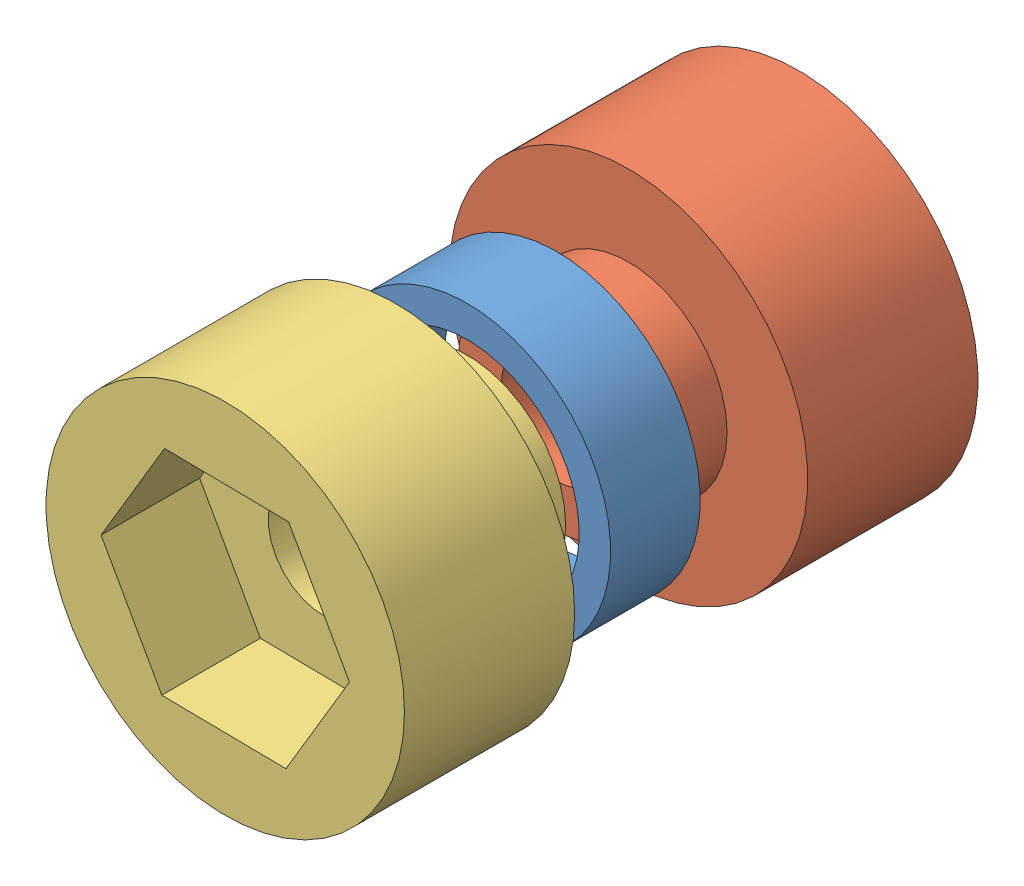
SolidWorks assembly 装配体1, configuration 默认. Lengths in mm.
Overall size (10 10 16).
3 component instances, 3 part files, 4 mates.
Components (placement in the parent):
- 实验1-2: 实验1 [默认] at (-0.2702 0.4 6.75) size (8 8 2.5)
- 实验2-1: 实验2 [默认] at (-0.2702 0.4 0) size (10 10 6.75)
- 实验3-2: 实验3 [默认] at (-0.2702 0.4 16) x (-1 0 0) z (0 0 -1) size (10 10 6.75)
Mates (geometry in assembly coordinates):
- 同心2: concentric: circle of 实验1-2; circle of 实验2-1
- 距离1: distance = 2 mm: plane of 实验1-2 through (-0.2702 0.4 6.75) normal (0 0 -1); plane of 实验2-1 through (-0.2702 0.4 4.75) normal (0 0 1)
- 同心4: concentric: cylinder of 实验1-2 through (-0.2702 0.4 9.25) axis (0 0 -1) radius 4; cylinder of 实验3-2 through (-0.2702 0.4 9.25) axis (0 0 1) radius 2.75
- 同心5: concentric: circle of 实验1-2; circle of 实验3-2
